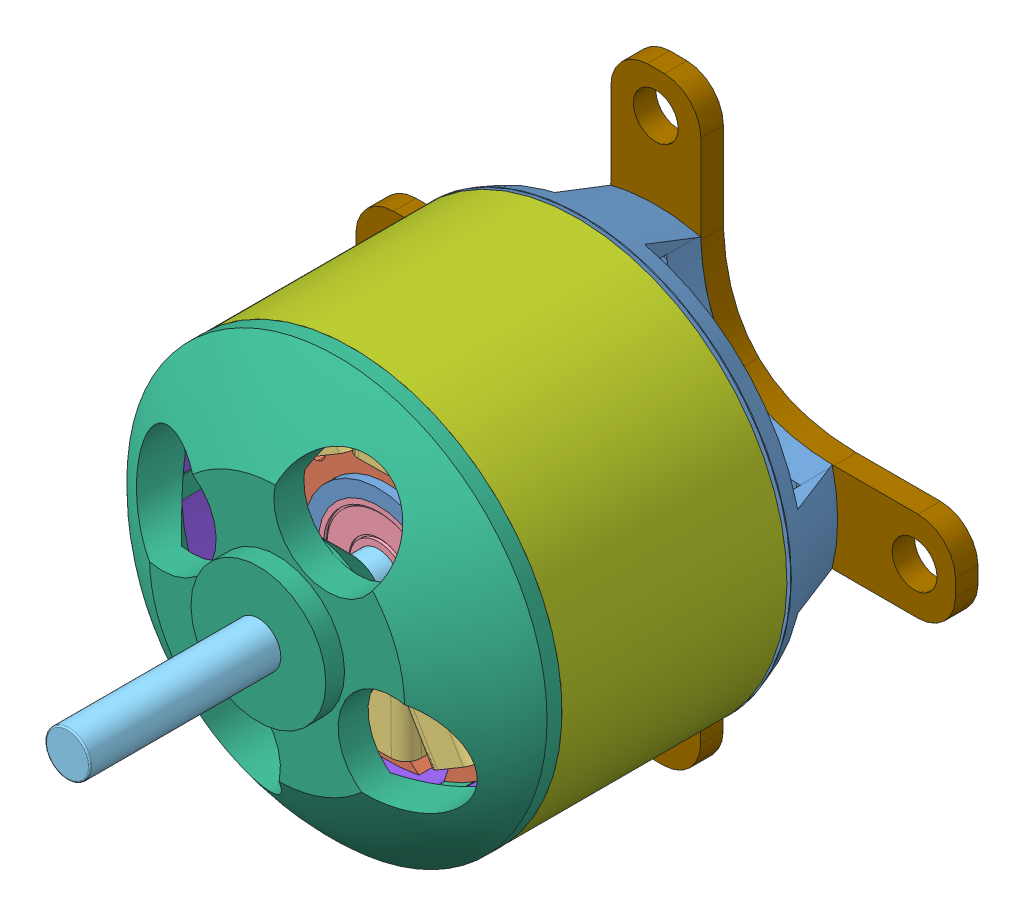
SolidWorks assembly BLDC motor, configuration Default. Lengths in mm.
Overall size (40.24 40.24 40.73).
36 component instances, 9 part files, 5 mates.
Components (placement in the parent):
- motor_stator-1: motor_stator [Default] at (4.4037 -1.9235 -1.092) size (28 28 18.85)
  - base-1: base [Default] at (10.5479 11.9817 13.9786) size (28 28 18.5)
  - armature-1: armature [Default] at (10.5479 11.9817 19.8988) x (0.999929 0.011943 0) z (0 0 1) size (22 22 12)
  - wire-1: wire [Default] at (10.4725 18.2982 25.8988) x (0.999929 0.011943 0) z (0 0 1) size (4 3.6 13.66)
  - wire-2: wire [Default] at (13.6409 17.4897 25.8988) x (0.871935 -0.489621 0) z (0 0 1) size (4 3.6 13.66)
  - wire-3: wire [Default] at (15.9805 15.2053 25.8988) x (0.510307 -0.859992 0) z (0 0 1) size (4 3.6 13.66)
  - wire-4: wire [Default] at (16.8645 12.0571 25.8988) x (0.011943 -0.999929 0) z (0 0 1) size (4 3.6 13.66)
  - wire-5: wire [Default] at (16.056 8.8887 25.8988) x (-0.489621 -0.871935 0) z (0 0 1) size (4 3.6 13.66)
  - wire-6: wire [Default] at (13.7716 6.5491 25.8988) x (-0.859992 -0.510307 0) z (0 0 1) size (4 3.6 13.66)
  - wire-7: wire [Default] at (10.6234 5.6651 25.8988) x (-0.999929 -0.011943 0) z (0 0 1) size (4 3.6 13.66)
  - wire-8: wire [Default] at (7.455 6.4736 25.8988) x (-0.871935 0.489621 0) z (0 0 1) size (4 3.6 13.66)
  - wire-9: wire [Default] at (5.1153 8.758 25.8988) x (-0.510307 0.859992 0) z (0 0 1) size (4 3.6 13.66)
  - wire-10: wire [Default] at (4.2314 11.9062 25.8988) x (-0.011943 0.999929 0) z (0 0 1) size (4 3.6 13.66)
  - wire-11: wire [Default] at (5.0399 15.0746 25.8988) x (0.489621 0.871935 0) z (0 0 1) size (4 3.6 13.66)
  - wire-12: wire [Default] at (7.3243 17.4143 25.8988) x (0.859992 0.510307 0) z (0 0 1) size (4 3.6 13.66)
  - bearing-1: bearing [Default] at (10.5479 11.9817 29.4786) x (0.999972 -0.007521 0) z (-0.007521 -0.999972 0) size (8 3 8)
  - bearing-2: bearing [Default] at (10.5479 11.9817 16.8786) x (-0.923728 -0.383049 0) z (0.383049 -0.923728 0) size (8 3 8)
- motor_rotor-1: motor_rotor [Default] at (-28.2386 -6.9448 43.2603) x (0.999243 -0.03891 0) z (0 0 1) size (38.76 38.76 40)
  - shaft-1: shaft [Default] at (42.4959 18.6707 -31.1458) size (3 3 40)
  - rotor_part-1: rotor_part [Default] at (42.4959 18.6707 -25.1237) x (0.930002 -0.367555 0) z (0 0 1) size (28 28 11.25)
  - ring-2: ring [Default] at (42.4959 18.6707 -25.1237) x (0.836625 -0.547775 0) z (0 0 1) size (28 28 15)
  - magnet-16: magnet [Default] at (42.4959 18.6707 -24.1237) x (0.997379 0.072352 0) z (0 0 1) size (4 1.15 14)
  - magnet-17: magnet [Default] at (42.4959 18.6707 -24.1237) x (0.867216 0.497932 0) z (0 0 1) size (4 1.15 14)
  - magnet-18: magnet [Default] at (42.4959 18.6707 -24.1237) x (0.565292 0.824891 0) z (0 0 1) size (4 1.15 14)
  - magnet-19: magnet [Default] at (42.4959 18.6707 -24.1237) x (0.151405 0.988472 0) z (0 0 1) size (4 1.15 14)
  - magnet-20: magnet [Default] at (42.4959 18.6707 -24.1237) x (-0.29247 0.956275 0) z (0 0 1) size (4 1.15 14)
  - magnet-21: magnet [Default] at (42.4959 18.6707 -24.1237) x (-0.678417 0.734677 0) z (0 0 1) size (4 1.15 14)
  - magnet-22: magnet [Default] at (42.4959 18.6707 -24.1237) x (-0.929996 0.367568 0) z (0 0 1) size (4 1.15 14)
  - magnet-23: magnet [Default] at (42.4959 18.6707 -24.1237) x (-0.99738 -0.072341 0) z (0 0 1) size (4 1.15 14)
  - magnet-24: magnet [Default] at (42.4959 18.6707 -24.1237) x (-0.867221 -0.497923 0) z (0 0 1) size (4 1.15 14)
  - magnet-25: magnet [Default] at (42.4959 18.6707 -24.1237) x (-0.5653 -0.824885 0) z (0 0 1) size (4 1.15 14)
  - magnet-26: magnet [Default] at (42.4959 18.6707 -24.1237) x (-0.151415 -0.98847 0) z (0 0 1) size (4 1.15 14)
  - magnet-27: magnet [Default] at (42.4959 18.6707 -24.1237) x (0.29246 -0.956278 0) z (0 0 1) size (4 1.15 14)
  - magnet-28: magnet [Default] at (42.4959 18.6707 -24.1237) x (0.678409 -0.734684 0) z (0 0 1) size (4 1.15 14)
  - magnet-29: magnet [Default] at (42.4959 18.6707 -24.1237) x (0.929993 -0.367578 0) z (0 0 1) size (4 1.15 14)
- clamp-1: clamp [Default] at (14.9516 10.0582 11.3866) size (40 40 1.52)
Mates (geometry in assembly coordinates):
- Concentric1: concentric: cylinder of assembly; cylinder of assembly; cylinder of motor_stator-1/bearing-1 through (14.9516 10.0582 31.3866) axis (0 0 -1) radius 1.5; cylinder of motor_rotor-1/shaft-1 through (14.9516 10.0582 52.1145) axis (0 0 -1) radius 1.5
- Distance1: distance = 0.25 mm: plane of assembly; plane of assembly; plane of motor_rotor-1/ring-2 through (14.9516 10.0582 18.1366) normal (0 0 -1); plane of motor_stator-1/base-1 through (14.9516 10.0582 17.8866) normal (0 0 1)
- Concentric2: concentric: cylinder of assembly; cylinder of assembly; cylinder of motor_stator-1/base-1 through (14.9516 18.0582 15.8866) axis (0 0 -1) radius 1.5; cylinder of clamp-1 through (14.9516 18.0582 12.8866) axis (0 0 -1) radius 1.4267
- Concentric3: concentric: cylinder of assembly; cylinder of assembly; cylinder of motor_stator-1/base-1 through (14.9516 2.0582 15.8866) axis (0 0 -1) radius 1.5; cylinder of clamp-1 through (14.9516 2.0582 14.3866) axis (0 0 -1) radius 1.5
- Coincident1: coincident: plane of assembly; plane of assembly; plane of motor_stator-1/base-1 through (14.9516 10.0582 12.8866) normal (0 0 -1); plane of clamp-1 through (14.9516 10.0582 12.8866) normal (0 0 1)
